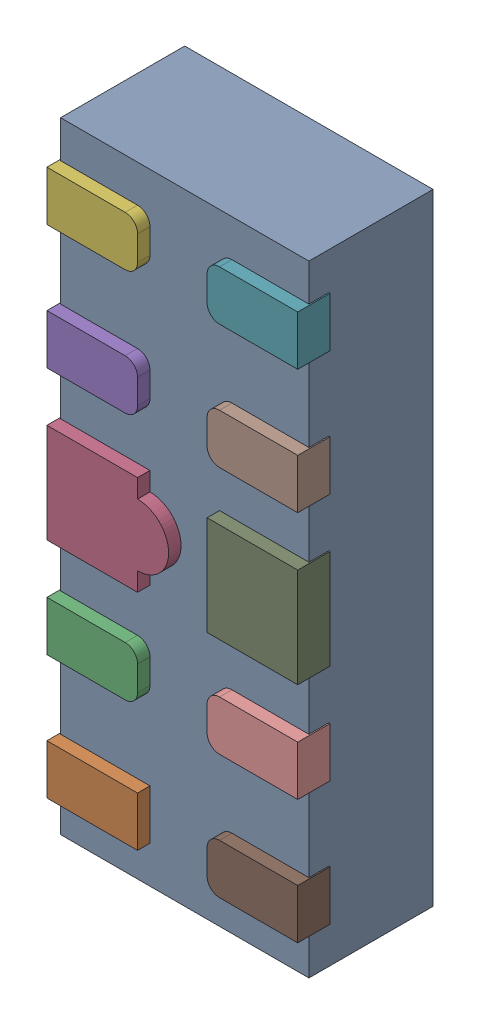
SolidWorks assembly D39, configuration Défaut. Lengths in mm.
Overall size (1.01 2.5 0.55).
12 component instances, 5 part files, 0 mates.
Components (placement in the parent):
- UDFN10-1: UDFN10 [Défaut] at (77.4897 -11.5768 -1.1719) x (0 1 0) z (-1 0 0) size (2.5 0.55 1.01)
  - User Library-UDFN10_Body-1: User Library-UDFN10_Body [Défaut] at (1.0785 0.9721 1.8983) size (2.5 0.5 1)
  - User Library-UDFN10_Pin1-1: User Library-UDFN10_Pin1 [Défaut] at (0.0785 1.0521 2.2208) x (0 0 -1) z (-1 0 0) size (0.37 0.13 0.2)
  - User Library-UDFN10_Pin2-1: User Library-UDFN10_Pin2 [Défaut] at (0.5785 1.0521 2.2208) x (0 0 1) z (1 0 0) size (0.37 0.13 0.2)
  - User Library-UDFN10_Pin4-1: User Library-UDFN10_Pin4 [Défaut] at (1.0785 0.9221 2.2208) x (0 0 1) z (-1 0 0) size (0.49 0.13 0.4)
  - User Library-UDFN10_Pin2-2: User Library-UDFN10_Pin2 [Défaut] at (1.5785 0.9221 2.2208) x (0 0 1) z (-1 0 0) size (0.37 0.13 0.2)
  - User Library-UDFN10_Pin2-3: User Library-UDFN10_Pin2 [Défaut] at (2.0785 0.9221 2.2208) x (0 0 1) z (-1 0 0) size (0.37 0.13 0.2)
  - User Library-UDFN10_Pin2-4: User Library-UDFN10_Pin2 [Défaut] at (2.0785 0.9221 1.5758) x (0 0 -1) z (1 0 0) size (0.37 0.13 0.2)
  - User Library-UDFN10_Pin2-5: User Library-UDFN10_Pin2 [Défaut] at (1.5785 0.9221 1.5758) x (0 0 -1) z (1 0 0) size (0.37 0.13 0.2)
  - User Library-UDFN10_Pin3-1: User Library-UDFN10_Pin3 [Défaut] at (1.0785 0.9221 1.5758) x (0 0 1) z (-1 0 0) size (0.37 0.13 0.4)
  - User Library-UDFN10_Pin2-6: User Library-UDFN10_Pin2 [Défaut] at (0.5785 0.9221 1.5758) x (0 0 -1) z (1 0 0) size (0.37 0.13 0.2)
  - User Library-UDFN10_Pin2-7: User Library-UDFN10_Pin2 [Défaut] at (0.0785 0.9221 1.5758) x (0 0 -1) z (1 0 0) size (0.37 0.13 0.2)
